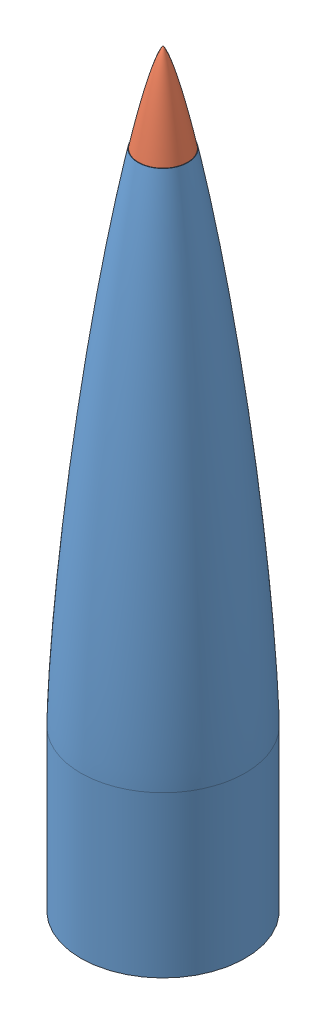
SolidWorks assembly S2_Nose_Cone, configuration Default. Lengths in mm.
Overall size (82.2 374.46 82.2).
2 component instances, 2 part files, 6 mates.
Components (placement in the parent):
- S2_NC_Nose_Cone-1: S2_NC_Nose_Cone [Default] x (0 -1 0) z (0 0 1) size (330.2 82.2 82.2)
- S2_NC_Nose_Cone_Tip-1: S2_NC_Nose_Cone_Tip [Default] x (0 -1 0) z (0 0 1) size (44.45 24.48 24.48)
Mates (geometry in assembly coordinates):
- Coincident1: coincident aligned: line of S2_NC_Nose_Cone-1 through (363.22 0 -27.957) axis (0 0 -1)
- Coincident2: coincident aligned: plane of S2_NC_Nose_Cone-1 through (0 0 0) normal (0 0 1)
- Coincident3: coincident anti-aligned: plane of S2_NC_Nose_Cone-1 through (0 0 0) normal (0 -1 0)
- Coincident4: coincident anti-aligned: line of S2_NC_Nose_Cone_Tip-1 through (48.895 0 -46.6725) axis (0 0 1)
- Parallel1: parallel aligned: plane of S2_NC_Nose_Cone_Tip-1 through (0 0 0) normal (0 0 1)
- Coincident7: coincident anti-aligned: plane of S2_NC_Nose_Cone_Tip-1 through (0 0 0) normal (0 -1 0)
